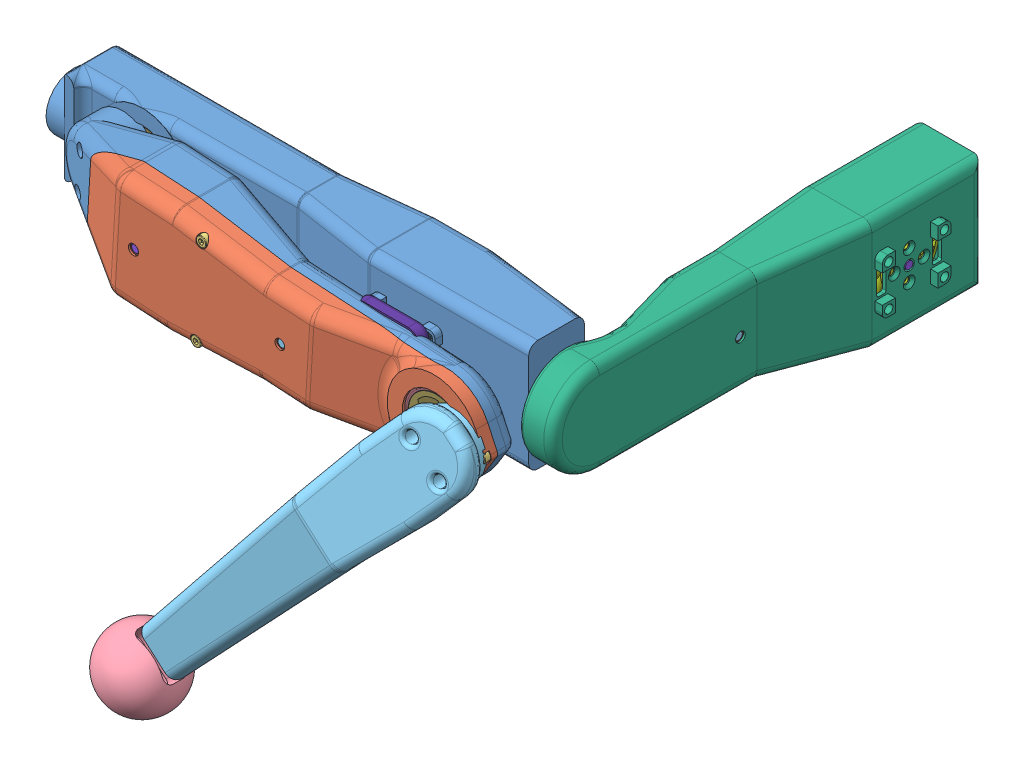
SolidWorks assembly LIMB_ASSEMBLY, configuration Default. Lengths in mm.
Overall size (306 242.39 272.91).
134 component instances, 43 part files, 6 mates.
Components (placement in the parent):
- SHOULDER_ASSEMBLY-1: SHOULDER_ASSEMBLY [Default] at (272.4901 -79.7457 65.6363) x (-1 0 0) z (0 1 0) size (272 49 60)
  - SHOULDER_MODULE-1: SHOULDER_MODULE [Default] at (56.0604 170.3399 241.2953) size (272 41 60)
  - Reduction_module-1: Reduction_module [Default] at (126.5679 123.0145 230.5234) x (0.986065 0 -0.166359) z (0.166359 0 0.986065) size (46.5 23.1 46.5)
    - BEARING_MR84-2RS_4x8x2mm.step-2: BEARING_MR84-2RS_4x8x2mm.step [Default] at (6.5822 30.8254 12.0346) x (0.704016 0 0.710185) z (0 -1 0) size (8 8 2)
    - DRIVEN_PULLEY_FIRST_REDUCTION-1: DRIVEN_PULLEY_FIRST_REDUCTION [По умолчанию] at (6.5822 31.8754 12.0346) x (0.983912 0 0.178656) z (0 1 0) size (40 40 8.1)
    - GT2_driving_pulley_second_reduction-1: GT2_driving_pulley_second_reduction [Default] at (6.5822 37.4254 12.0346) x (0.960792 0 -0.27727) z (0 -1 0) size (16 16 16)
    - REDUCTION_SHAFT-1: REDUCTION_SHAFT [Default] at (6.5822 41.3754 12.0346) size (4 23.1 4)
    - BEARING_MR84-2RS_4x8x2mm.step-3: BEARING_MR84-2RS_4x8x2mm.step [Default] at (6.5822 51.9254 12.0346) x (-0.641213 0 -0.767363) z (0 -1 0) size (8 8 2)
    - bearing_spacer_1mm-1: bearing_spacer_1mm [Default] at (6.5822 31.8254 12.0346) x (0.908927 0 0.416955) z (-0.416955 0 0.908927) size (5.2 1 5.2)
    - bearing_spacer_1mm-2: bearing_spacer_1mm [Default] at (6.5822 49.9254 12.0346) size (5.2 1 5.2)
  - Actuator_Module-1: Actuator_Module [Default] at (32.1417 199.8019 282.6675) x (1 0 0) z (0 0 -1) size (49.6 36 49.6)
    - BLDC_Motor_5010-1: BLDC_Motor_5010 [Varsayılan] at (23.9187 12.962 41.3722) size (49.6 20 49.6)
    - MOTOR_SHAFT-1: MOTOR_SHAFT [Default] at (23.9187 28.962 41.3722) x (-0.884655 0 0.466247) z (-0.466247 0 -0.884655) size (4 36 4)
    - Gates_2GT_20T_Toothed_Pulley-1: Gates_2GT_20T_Toothed_Pulley [Výchozí] at (23.9187 27.862 41.3722) x (0.949687 0 0.313202) z (-0.313202 0 0.949687) size (15 9.4 15)
    - BEARING_MR84-2RS_4x8x2mm.step-4: BEARING_MR84-2RS_4x8x2mm.step [Default] at (23.9187 45.962 41.3722) x (-0.723388 0 -0.690442) z (0 -1 0) size (8 8 2)
    - pulley-motor-interface-1: pulley-motor-interface [Default] at (23.9187 32.962 41.3722) size (20 2.5 20)
    - bearing_spacer_1mm-1: bearing_spacer_1mm [Default] at (23.9187 43.862 41.3722) size (5.2 1 5.2)
    - socket countersunk head screw_din-1: socket countersunk head screw_din [DIN 7991 - M3 x 8 --- 4.8N] at (29.9187 34.512 41.3722) x (0 -1 0) z (0.002985 0 0.999996) size (8 5.7 5.7)
    - socket countersunk head screw_din-2: socket countersunk head screw_din [DIN 7991 - M3 x 8 --- 4.8N] at (23.9187 34.512 47.3722) x (0 -1 0) z (0.006654 0 0.999978) size (8 5.7 5.7)
    - socket countersunk head screw_din-3: socket countersunk head screw_din [DIN 7991 - M3 x 8 --- 4.8N] at (17.9187 34.512 41.3722) x (0 -1 0) z (-0.019944 0 0.999801) size (8 5.7 5.7)
    - socket countersunk head screw_din-4: socket countersunk head screw_din [DIN 7991 - M3 x 8 --- 4.8N] at (23.9187 34.512 35.3722) x (0 -1 0) z (-0.046377 0 0.998924) size (8 5.7 5.7)
  - Second_reduction_module-1: Second_reduction_module [Default] at (219.9841 185.8856 208.4174) x (-0.999944 0 -0.01057) z (-0.01057 0 0.999944) size (37.7 15.5 37.7)
    - DRIVEN_PULLEY_SECOND_REDUCTION-1: DRIVEN_PULLEY_SECOND_REDUCTION [По умолчанию] at (8.5756 23.3079 32.9704) x (-1 0 0) z (0 -1 0) size (37.7 37.7 15.5)
    - Bearings_6706-2RS.stp-1: Bearings_6706-2RS.stp [Default] at (8.5756 23.7518 32.9704) x (0 1 0) z (0 0 -1) size (3.99 37.01 37.01)
    - Bearings_6706-2RS.stp-2: Bearings_6706-2RS.stp [Default] at (8.5756 12.264 32.9704) x (0 1 0) z (0 0 1) size (3.99 37.01 37.01)
    - M3_INSERT.step-1: M3_INSERT.step [Default] at (8.5756 10.2579 42.9704) size (4.52 4 4.53)
    - M3_INSERT.step-2: M3_INSERT.step [Default] at (8.5756 10.2579 22.9704) size (4.52 4 4.53)
  - socket countersunk head screw_din-1: socket countersunk head screw_din [DIN 7991 - M3 x 8 --- 4.8N] at (64.0604 188.8899 241.2953) x (0 -1 0) z (0.506676 0 0.862137) size (8 5.7 5.7)
  - socket countersunk head screw_din-2: socket countersunk head screw_din [DIN 7991 - M3 x 8 --- 4.8N] at (56.0604 188.8899 249.2953) x (0 -1 0) z (0 0 1) size (8 5.7 5.7)
  - socket countersunk head screw_din-3: socket countersunk head screw_din [DIN 7991 - M3 x 8 --- 4.8N] at (48.0604 188.8899 241.2953) x (0 -1 0) z (0 0 1) size (8 5.7 5.7)
  - socket countersunk head screw_din-4: socket countersunk head screw_din [DIN 7991 - M3 x 8 --- 4.8N] at (56.0604 188.8899 233.2953) x (0 -1 0) z (0 0 1) size (8 5.7 5.7)
  - M3_INSERT.step-1: M3_INSERT.step [Default] at (41.0604 190.8399 230.2953) x (-1 0 0) z (0 0 1) size (4.52 4 4.53)
  - M3_INSERT.step-2: M3_INSERT.step [Default] at (71.0604 192.8399 230.2953) x (1 0 0) z (0 0 -1) size (4.52 4 4.53)
  - M3_INSERT.step-3: M3_INSERT.step [Default] at (41.0604 192.8399 252.2953) x (-1 0 0) z (0 0 1) size (4.52 4 4.53)
  - M3_INSERT.step-4: M3_INSERT.step [Default] at (71.0604 192.8399 252.2953) x (-1 0 0) z (0 0 1) size (4.52 4 4.53)
  - Encoder_magnet-1: Encoder_magnet [Default] at (56.0604 188.8399 241.2953) size (4 1.5 4)
  - AS5048a Magnetic Encoder.step-1: AS5048a Magnetic Encoder.step [Default] at (53.463 192.8399 239.824) x (0 0 1) z (0 -1 0) size (15 17.37 2.2)
    - Component2.step-1: Component2.step [Default] at origin size (0.79 0.74 0.3)
    - Component6.step-1: Component6.step [Default] at origin size (0.79 0.36 0.28)
    - Component7.step-1: Component7.step [Default] at origin size (0.79 0.33 0.28)
    - Component10.step-1: Component10.step [Default] at origin size (0.36 2.99 0.05)
    - Component5.step-1: Component5.step [Default] at origin size (0.79 0.74 0.3)
    - Component9.step-1: Component9.step [Default] at origin size (0.79 0.33 0.28)
    - Component8.step-1: Component8.step [Default] at origin size (0.79 0.36 0.28)
    - Component4.step-1: Component4.step [Default] at origin size (0.36 2.99 0.05)
    - Component3.step-1: Component3.step [Default] at origin size (0.36 2.99 0.05)
    - Component17.step-1: Component17.step [Default] at origin size (5.39 6.68 1.2)
    - Component15.step-1: Component15.step [Default] at origin size (0.36 2.99 0.05)
    - Component14.step-1: Component14.step [Default] at origin size (0.39 2.99 0.05)
    - Component18.step-1: Component18.step [Default] at origin size (0.33 2.67 0.05)
    - Component19.step-1: Component19.step [Default] at origin size (1.7 2.63 0.05)
    - Component11.step-1: Component11.step [Default] at origin size (1.7 2.63 0.05)
    - Component12.step-1: Component12.step [Default] at origin size (0.33 2.99 0.05)
    - Component16.step-1: Component16.step [Default] at origin size (1.7 2.63 0.05)
    - Component13.step-1: Component13.step [Default] at origin size (0.35 2.67 0.05)
    - Magnetic Encoder.step-1: Magnetic Encoder.step [Default] at origin size (15 17.37 1)
  - ENCODER_HOUSING-1: ENCODER_HOUSING [Default] at (56.0604 194.3399 241.2953) x (0 0 -1) z (-1 0 0) size (36.04 6.5 36.04)
- LEG_ASSEMBLY-1: LEG_ASSEMBLY [Default] at (84.8926 418.7945 144.0555) x (0.998198 -0.060006 0) z (-0.060006 -0.998198 0) size (248 47.27 60)
  - Actuator_Module-1: Actuator_Module [Default] at (5.9246 93.1833 215.532) size (49.6 36 49.6)
    - BLDC_Motor_5010-1: BLDC_Motor_5010 [Varsayılan] at (23.9187 12.962 41.3722) size (49.6 20 49.6)
    - MOTOR_SHAFT-1: MOTOR_SHAFT [Default] at (23.9187 28.962 41.3722) x (-0.884655 0 0.466247) z (-0.466247 0 -0.884655) size (4 36 4)
    - Gates_2GT_20T_Toothed_Pulley-1: Gates_2GT_20T_Toothed_Pulley [Výchozí] at (23.9187 27.862 41.3722) x (0.949687 0 0.313202) z (-0.313202 0 0.949687) size (15 9.4 15)
    - BEARING_MR84-2RS_4x8x2mm.step-4: BEARING_MR84-2RS_4x8x2mm.step [Default] at (23.9187 45.962 41.3722) x (-0.723388 0 -0.690442) z (0 -1 0) size (8 8 2)
    - pulley-motor-interface-1: pulley-motor-interface [Default] at (23.9187 32.962 41.3722) size (20 2.5 20)
    - bearing_spacer_1mm-1: bearing_spacer_1mm [Default] at (23.9187 43.862 41.3722) size (5.2 1 5.2)
    - socket countersunk head screw_din-1: socket countersunk head screw_din [DIN 7991 - M3 x 8 --- 4.8N] at (29.9187 34.512 41.3722) x (0 -1 0) z (0.002985 0 0.999996) size (8 5.7 5.7)
    - socket countersunk head screw_din-2: socket countersunk head screw_din [DIN 7991 - M3 x 8 --- 4.8N] at (23.9187 34.512 47.3722) x (0 -1 0) z (0.006654 0 0.999978) size (8 5.7 5.7)
    - socket countersunk head screw_din-3: socket countersunk head screw_din [DIN 7991 - M3 x 8 --- 4.8N] at (17.9187 34.512 41.3722) x (0 -1 0) z (-0.019944 0 0.999801) size (8 5.7 5.7)
    - socket countersunk head screw_din-4: socket countersunk head screw_din [DIN 7991 - M3 x 8 --- 4.8N] at (23.9187 34.512 35.3722) x (0 -1 0) z (-0.046377 0 0.998924) size (8 5.7 5.7)
  - Reduction_module-1: Reduction_module [Default] at (122.5557 169.9706 256.5456) x (-0.502623 0 -0.864506) z (-0.864506 0 0.502623) size (46.5 23.1 46.5)
    - BEARING_MR84-2RS_4x8x2mm.step-2: BEARING_MR84-2RS_4x8x2mm.step [Default] at (6.5822 30.8254 12.0346) x (0.704016 0 0.710185) z (0 -1 0) size (8 8 2)
    - DRIVEN_PULLEY_FIRST_REDUCTION-1: DRIVEN_PULLEY_FIRST_REDUCTION [По умолчанию] at (6.5822 31.8754 12.0346) x (0.983912 0 0.178656) z (0 1 0) size (40 40 8.1)
    - GT2_driving_pulley_second_reduction-1: GT2_driving_pulley_second_reduction [Default] at (6.5822 37.4254 12.0346) x (0.960792 0 -0.27727) z (0 -1 0) size (16 16 16)
    - REDUCTION_SHAFT-1: REDUCTION_SHAFT [Default] at (6.5822 41.3754 12.0346) size (4 23.1 4)
    - BEARING_MR84-2RS_4x8x2mm.step-3: BEARING_MR84-2RS_4x8x2mm.step [Default] at (6.5822 51.9254 12.0346) x (-0.641213 0 -0.767363) z (0 -1 0) size (8 8 2)
    - bearing_spacer_1mm-1: bearing_spacer_1mm [Default] at (6.5822 31.8254 12.0346) x (0.908927 0 0.416955) z (-0.416955 0 0.908927) size (5.2 1 5.2)
    - bearing_spacer_1mm-2: bearing_spacer_1mm [Default] at (6.5822 49.9254 12.0346) size (5.2 1 5.2)
  - Encoder_magnet-1: Encoder_magnet [Default] at (29.8433 102.6453 256.9041) x (0.937581 0 0.347767) z (-0.347767 0 0.937581) size (4 1.5 4)
  - Second_reduction_module-1: Second_reduction_module [Default] at (151.6287 143.091 264.4791) x (0.460617 0 0.887599) z (0.887599 0 -0.460617) size (37.7 15.5 37.7)
    - DRIVEN_PULLEY_SECOND_REDUCTION-1: DRIVEN_PULLEY_SECOND_REDUCTION [По умолчанию] at (8.5756 23.3079 32.9704) x (-1 0 0) z (0 -1 0) size (37.7 37.7 15.5)
    - Bearings_6706-2RS.stp-1: Bearings_6706-2RS.stp [Default] at (8.5756 23.7518 32.9704) x (0 1 0) z (0 0 -1) size (3.99 37.01 37.01)
    - Bearings_6706-2RS.stp-2: Bearings_6706-2RS.stp [Default] at (8.5756 12.264 32.9704) x (0 1 0) z (0 0 1) size (3.99 37.01 37.01)
    - M3_INSERT.step-1: M3_INSERT.step [Default] at (8.5756 10.2579 42.9704) size (4.52 4 4.53)
    - M3_INSERT.step-2: M3_INSERT.step [Default] at (8.5756 10.2579 22.9704) size (4.52 4 4.53)
  - ENCODER_HOUSING-1: ENCODER_HOUSING [Default] at (29.8433 97.6453 256.9041) x (-1 0 0) z (0 0 1) size (36.04 6.5 36.04)
  - M3_INSERT.step-2: M3_INSERT.step [Default] at (41.8633 100.1453 268.9241) x (0.990313 0 -0.138851) z (0.138851 0 0.990313) size (4.52 4 4.53)
  - M3_INSERT.step-3: M3_INSERT.step [Default] at (17.8233 100.1453 268.9241) x (-0.211556 0 -0.977366) z (0.977366 0 -0.211556) size (4.52 4 4.53)
  - M3_INSERT.step-4: M3_INSERT.step [Default] at (41.8633 100.1453 244.8841) x (0.848747 0 -0.5288) z (0.5288 0 0.848747) size (4.52 4 4.53)
  - M3_INSERT.step-5: M3_INSERT.step [Default] at (17.8233 100.1453 244.8841) x (0.728724 0 -0.684808) z (0.684808 0 0.728724) size (4.52 4 4.53)
  - encoder_TLE5012-1: encoder_TLE5012 [Default] at (29.8433 98.6453 256.9041) size (30.04 2.5 30.04)
  - LEG_MODULE_BOTTOM-1: LEG_MODULE_BOTTOM [Default] at (29.8433 122.6453 256.9041) x (1 0 0) z (0 0 -1) size (248 33.55 60)
  - LEG_MODULE_TOP-1: LEG_MODULE_TOP [Default] at (29.8433 122.6453 256.9041) x (1 0 0) z (0 0 -1) size (220.5 13.77 60)
  - M3_INSERT.step-6: M3_INSERT.step [Default] at (141.8433 127.6453 236.4041) size (4.52 4 4.53)
  - M3_INSERT.step-7: M3_INSERT.step [Default] at (141.8433 127.6453 277.4041) size (4.52 4 4.53)
  - M3_INSERT.step-8: M3_INSERT.step [Default] at (64.8433 127.6453 280.8817) x (1 0 0) z (0 0 -1) size (4.52 4 4.53)
  - M3_INSERT.step-9: M3_INSERT.step [Default] at (64.8433 127.6453 232.9266) x (1 0 0) z (0 0 -1) size (4.52 4 4.53)
  - M3_INSERT.step-10: M3_INSERT.step [Default] at (209.8433 127.6453 256.9041) x (0.998959 0 0.045621) z (0.045621 0 -0.998959) size (4.52 4 4.53)
  - socket head cap screw_din-3: socket head cap screw_din [DIN 912 M3 x 12 --- 12N] at (141.8433 116.0453 236.4041) x (0 1 0) z (0 0 1) size (15 5.5 5.5)
  - socket head cap screw_din-4: socket head cap screw_din [DIN 912 M3 x 12 --- 12N] at (141.8433 116.0453 277.4041) x (0 1 0) z (0 0 1) size (15 5.5 5.5)
  - socket head cap screw_din-5: socket head cap screw_din [DIN 912 M3 x 10 --- 10N] at (209.8433 134.1453 256.9041) x (0 -1 0) z (0 0 1) size (13 5.5 5.5)
  - socket head cap screw_din-6: socket head cap screw_din [DIN 912 M3 x 16 --- 16N] at (64.8433 141.1453 280.8817) x (0 -1 0) z (0 0 1) size (19 5.5 5.5)
  - socket head cap screw_din-8: socket head cap screw_din [DIN 912 M3 x 16 --- 16N] at (64.8433 141.1453 232.9266) x (0 -1 0) z (0 0 1) size (19 5.5 5.5)
  - socket countersunk head screw_din-2: socket countersunk head screw_din [DIN 7991 - M3 x 8 --- 4.8N] at (29.8433 104.0953 247.4041) x (0 1 0) z (-0.007855 0 0.999969) size (8 5.7 5.7)
  - socket countersunk head screw_din-3: socket countersunk head screw_din [DIN 7991 - M3 x 8 --- 4.8N] at (37.8433 104.0953 256.9041) x (0 1 0) z (0.008136 0 0.999967) size (8 5.7 5.7)
  - socket countersunk head screw_din-4: socket countersunk head screw_din [DIN 7991 - M3 x 8 --- 4.8N] at (21.8433 104.0953 256.9041) x (0 1 0) z (0.007396 0 0.999973) size (8 5.7 5.7)
  - socket countersunk head screw_din-5: socket countersunk head screw_din [DIN 7991 - M3 x 8 --- 4.8N] at (29.8433 104.0953 266.4041) x (0 1 0) z (0.005455 0 0.999985) size (8 5.7 5.7)
  - socket countersunk head screw_din-7: socket countersunk head screw_din [DIN 7991 - M3 x 8 --- 4.8N] at (17.7811 97.5953 244.7865) x (0 1 0) z (-0.03444 0 0.999407) size (8 5.7 5.7)
  - socket countersunk head screw_din-8: socket countersunk head screw_din [DIN 7991 - M3 x 8 --- 4.8N] at (17.7988 97.5953 268.9386) x (0 1 0) z (-0.029949 0 0.999551) size (8 5.7 5.7)
  - socket countersunk head screw_din-9: socket countersunk head screw_din [DIN 7991 - M3 x 8 --- 4.8N] at (41.8812 97.5953 268.9381) x (0 1 0) z (0.000234 0 1) size (8 5.7 5.7)
  - socket countersunk head screw_din-10: socket countersunk head screw_din [DIN 7991 - M3 x 8 --- 4.8N] at (41.8891 97.5953 244.8529) x (0 1 0) z (-0.035147 0 0.999382) size (8 5.7 5.7)
- LOWER_LEG_ASSEMBLY-1: LOWER_LEG_ASSEMBLY [Default] at (223.6136 103.4465 240.1044) x (-0.659754 -0.751482 0) z (-0.751482 0.659754 0) size (264.38 40.5 40.01)
  - foot-1: foot [Default] at (163.4965 57.2841 -0.5063) x (0 1 0) z (0 0 -1) size (40 38.91 40)
  - LOWER_LEG_MODULE-1: LOWER_LEG_MODULE [Default] at (3.4965 60.7841 -0.4954) size (224.38 33.97 40)
- GROUND_LIMB_ASSEMBLY-1: GROUND_LIMB_ASSEMBLY [Default] at (157.897 -17.0791 98.2849) size (41 60 220)
  - GROUND_MODULE-2: GROUND_MODULE [Default] at (140.0326 178.6287 -13.8087) x (0 0 1) z (0 1 0) size (220 41 60)
  - Reduction_module-1: Reduction_module [Default] at (92.7072 192.0832 62.5204) x (0 -0.641504 -0.76712) z (0 -0.76712 0.641504) size (46.5 23.1 46.5)
    - BEARING_MR84-2RS_4x8x2mm.step-2: BEARING_MR84-2RS_4x8x2mm.step [Default] at (6.5822 30.8254 12.0346) x (0.704016 0 0.710185) z (0 -1 0) size (8 8 2)
    - DRIVEN_PULLEY_FIRST_REDUCTION-1: DRIVEN_PULLEY_FIRST_REDUCTION [По умолчанию] at (6.5822 31.8754 12.0346) x (0.983912 0 0.178656) z (0 1 0) size (40 40 8.1)
    - GT2_driving_pulley_second_reduction-1: GT2_driving_pulley_second_reduction [Default] at (6.5822 37.4254 12.0346) x (0.960792 0 -0.27727) z (0 -1 0) size (16 16 16)
    - REDUCTION_SHAFT-1: REDUCTION_SHAFT [Default] at (6.5822 41.3754 12.0346) size (4 23.1 4)
    - BEARING_MR84-2RS_4x8x2mm.step-3: BEARING_MR84-2RS_4x8x2mm.step [Default] at (6.5822 51.9254 12.0346) x (-0.641213 0 -0.767363) z (0 -1 0) size (8 8 2)
    - bearing_spacer_1mm-1: bearing_spacer_1mm [Default] at (6.5822 31.8254 12.0346) x (0.908927 0 0.416955) z (-0.416955 0 0.908927) size (5.2 1 5.2)
    - bearing_spacer_1mm-2: bearing_spacer_1mm [Default] at (6.5822 49.9254 12.0346) size (5.2 1 5.2)
  - Actuator_Module-1: Actuator_Module [Default] at (169.4946 202.5474 27.5634) x (0 -1 0) z (0 0 -1) size (49.6 36 49.6)
    - BLDC_Motor_5010-1: BLDC_Motor_5010 [Varsayılan] at (23.9187 12.962 41.3722) size (49.6 20 49.6)
    - MOTOR_SHAFT-1: MOTOR_SHAFT [Default] at (23.9187 28.962 41.3722) x (-0.884655 0 0.466247) z (-0.466247 0 -0.884655) size (4 36 4)
    - Gates_2GT_20T_Toothed_Pulley-1: Gates_2GT_20T_Toothed_Pulley [Výchozí] at (23.9187 27.862 41.3722) x (0.949687 0 0.313202) z (-0.313202 0 0.949687) size (15 9.4 15)
    - BEARING_MR84-2RS_4x8x2mm.step-4: BEARING_MR84-2RS_4x8x2mm.step [Default] at (23.9187 45.962 41.3722) x (-0.723388 0 -0.690442) z (0 -1 0) size (8 8 2)
    - pulley-motor-interface-1: pulley-motor-interface [Default] at (23.9187 32.962 41.3722) size (20 2.5 20)
    - bearing_spacer_1mm-1: bearing_spacer_1mm [Default] at (23.9187 43.862 41.3722) size (5.2 1 5.2)
    - socket countersunk head screw_din-1: socket countersunk head screw_din [DIN 7991 - M3 x 8 --- 4.8N] at (29.9187 34.512 41.3722) x (0 -1 0) z (0.002985 0 0.999996) size (8 5.7 5.7)
    - socket countersunk head screw_din-2: socket countersunk head screw_din [DIN 7991 - M3 x 8 --- 4.8N] at (23.9187 34.512 47.3722) x (0 -1 0) z (0.006654 0 0.999978) size (8 5.7 5.7)
    - socket countersunk head screw_din-3: socket countersunk head screw_din [DIN 7991 - M3 x 8 --- 4.8N] at (17.9187 34.512 41.3722) x (0 -1 0) z (-0.019944 0 0.999801) size (8 5.7 5.7)
    - socket countersunk head screw_din-4: socket countersunk head screw_din [DIN 7991 - M3 x 8 --- 4.8N] at (23.9187 34.512 35.3722) x (0 -1 0) z (-0.046377 0 0.998924) size (8 5.7 5.7)
Mates (geometry in assembly coordinates):
- Coincident1: coincident: plane of SHOULDER_ASSEMBLY-1/Second_reduction_module-1/DRIVEN_PULLEY_SECOND_REDUCTION-1 through (61.4297 161.5496 241.2639) normal (0 0 1); plane of LEG_ASSEMBLY-1/LEG_MODULE-1 through (61.4297 161.5496 241.2639) normal (0 0 -1)
- Concentric3: concentric: cylinder of SHOULDER_ASSEMBLY-1/SHOULDER_MODULE-1 through (61.4297 161.5496 261.9761) axis (0 0 -1) radius 17; cylinder of LEG_ASSEMBLY-1/LEG_MODULE-1 through (61.4297 161.5496 261.2639) axis (0 0 -1) radius 16.5
- Concentric4: concentric anti-aligned: cylinder of LEG_ASSEMBLY-1/LEG_MODULE-1 through (264.563 149.3384 303.2639) axis (0 0 -1) radius 17; cylinder of LOWER_LEG_ASSEMBLY-1/LOWER_LEG_MODULE-1 through (264.563 149.3384 276.8886) axis (0 0 1) radius 16.5
- Coincident2: coincident anti-aligned: plane of LEG_ASSEMBLY-1/Second_reduction_module-1/DRIVEN_PULLEY_SECOND_REDUCTION-1 through (253.987 151.2616 276.8886) normal (0 0 1); plane of LOWER_LEG_ASSEMBLY-1/LOWER_LEG_MODULE-1 through (264.563 149.3384 276.8886) normal (0 0 -1)
- Concentric5: concentric anti-aligned: cylinder of SHOULDER_ASSEMBLY-1/SHOULDER_MODULE-1 through (286.4297 161.5496 239.4761) axis (-1 0 0) radius 15; cylinder of GROUND_LIMB_ASSEMBLY-1/GROUND_MODULE-2 through (287.7297 161.5496 239.4761) axis (1 0 0) radius 18.5
- Coincident3: coincident anti-aligned: plane of SHOULDER_ASSEMBLY-1/SHOULDER_MODULE-1 through (286.4297 161.5496 239.4761) normal (1 0 0); plane of GROUND_LIMB_ASSEMBLY-1/GROUND_MODULE-2 through (286.4297 161.5496 239.4761) normal (-1 0 0)
